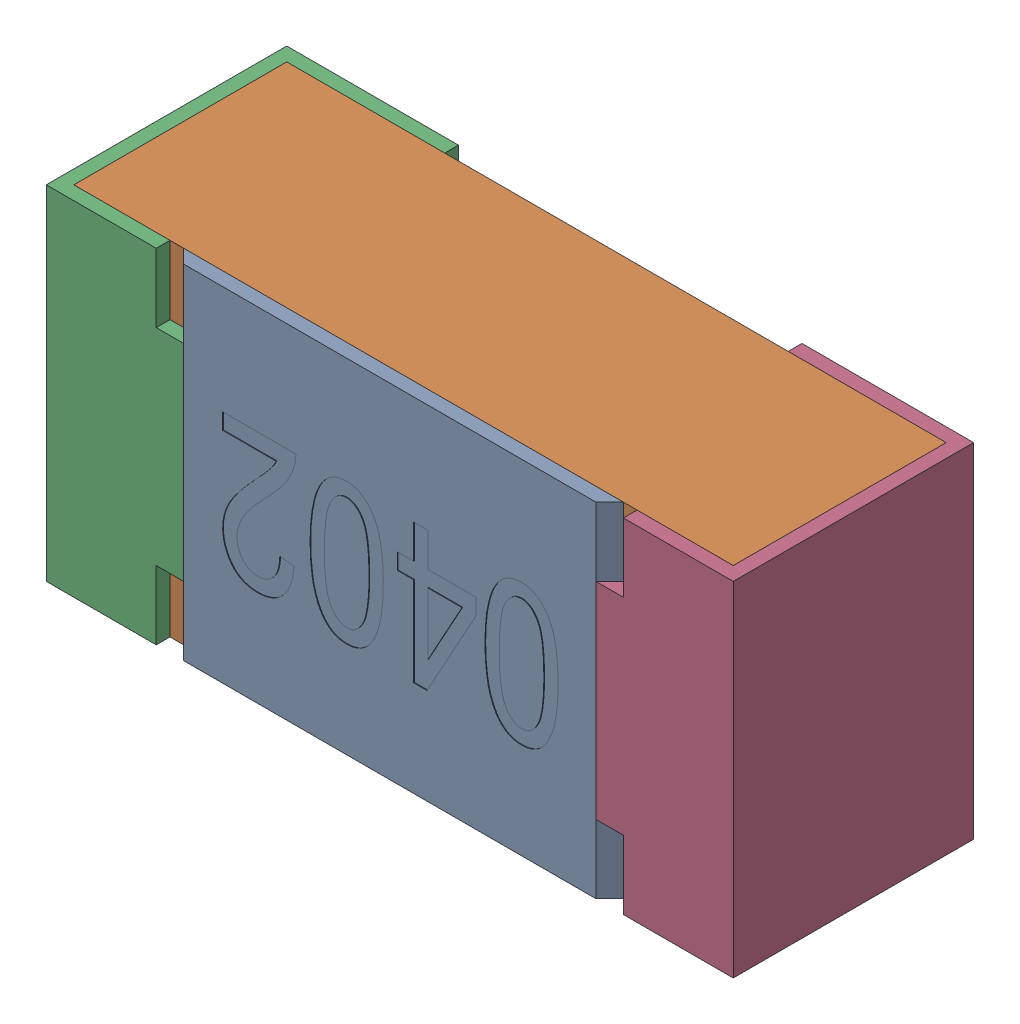
SolidWorks assembly R1, configuration Standard. Lengths in mm.
Overall size (1 0.5 0.35).
5 component instances, 4 part files, 0 mates.
Components (placement in the parent):
- R1-subassembly-1-1: R1-subassembly-1 [Standard] at (12.7999 -5.5 0) x (-1 0 0) z (0 0 1) size (1 0.5 0.35)
  - User Library-R_0402-1: User Library-R_0402 [Standard] at origin size (0.64 0.5 0.02)
  - User Library-R_0402-1-1: User Library-R_0402-1 [Standard] at origin size (0.96 0.5 0.31)
  - User Library-R_0402-2-1: User Library-R_0402-2 [Standard] at origin size (0.25 0.5 0.35)
  - User Library-R_0402-3-1: User Library-R_0402-3 [Standard] at origin size (0.25 0.5 0.35)
